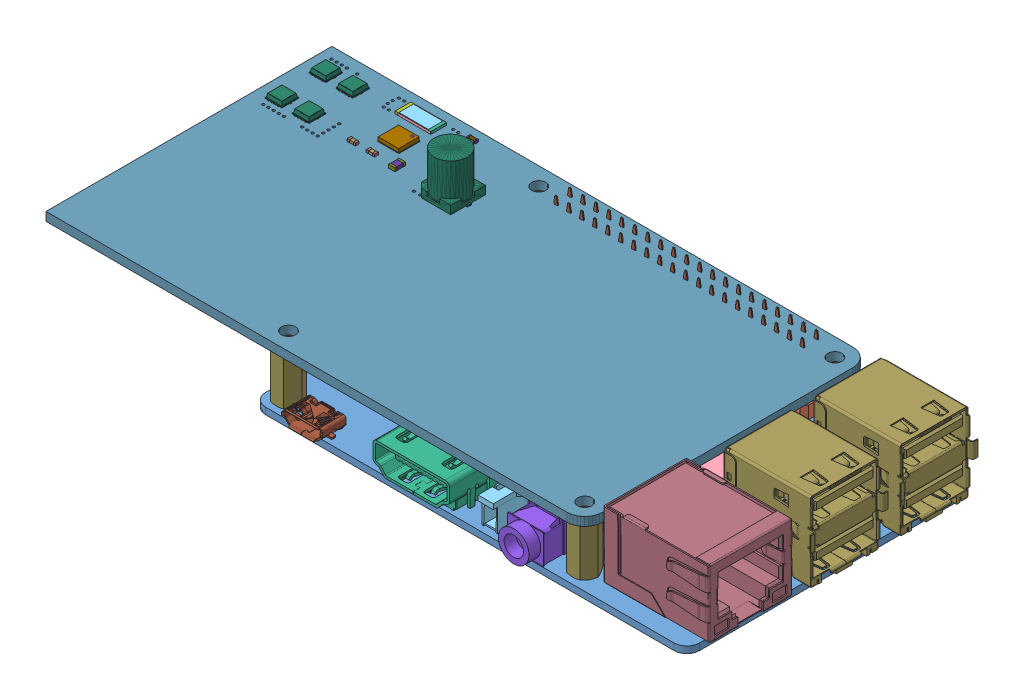
SolidWorks assembly RaspberryPi2 STEP214, configuration Default. Lengths in mm.
Overall size (130.68 29.46 66.29).
230 component instances, 66 part files, 14 mates.
Components (placement in the parent):
- Mainboard2-1: Mainboard2 [Default] at origin size (85 1.3 56)
- GPIO-1: GPIO [Default] at (-11.37 0 -24.5) x (0 0 1) z (-1 0 0) size (5 11.5 50.8)
- Processor-1: Processor [Default] at (-15.5 0 -3) x (0 0 1) z (-1 0 0) size (14 1 14)
- GPU-1: GPU [Default] at (15.25 0 -5.75) x (0 0 1) z (-1 0 0) size (9.1 1 9.1)
- CameraAssembly-1: CameraAssembly [Default] at (10.0885 -2.9159 16.55) x (-1 0 0) z (0 0 -1) size (6.09 6.17 23.84)
- CameraAssembly-2: CameraAssembly [Default] at (-46.3885 -2.9159 0) size (6.09 6.17 23.84)
- HDMI-1: HDMI [Default] at (-10.2 0.27 29.3) size (15 8.38 12.15)
- RAM-1: RAM [Default] at (0.5 -2.3 -6) x (0 0 1) z (-1 0 0) size (12 1 12)
- Audio-1: Audio [Default] at (10.9 0.15 21.75) size (7 6 14.8)
- MicroSDSocket-1: MicroSDSocket [Default] at (-34.5 -1.3 -0.7) x (0 0 -1) z (-1 0 0) size (13 1.3 14)
- MicroSD-1: MicroSD [Default] at (-37 -2.3 0.1) x (0 0 1) z (-1 0 0) size (11.29 1 15)
- micro USB2-1: micro USB2 [Default] at (-17.2704 -5.0969 44.9026) size (22.78 22.78 22.78)
- usb double-1: usb double [Default] at (30.38 -0.09 -18.85) x (0 0 -1) z (1 0 0) size (15.6 18.75 17.92)
- usb double-2: usb double [Default] at (30.38 -0.09 -1.25) x (0 0 -1) z (1 0 0) size (15.6 18.75 17.92)
- RJ45-LED-1: RJ45-LED [Default] at (34.11 7.4 17.348) x (1 0 0) z (0 -1 0) size (24.17 19.48 18.18)
- Motor_Control_Board-1: Motor_Control_Board [Default] at (-170 11.6914 170) x (1 0 0) z (0 1 0) size (105.51 56.01 9.74)
  - Board-1: Board [Default] at (0 0 -1.6914) size (105.51 56.01 1.69)
  - C1-1: C1 [Default] at origin size (7.39 6.81 8.05)
    - PCAP_6_3x7_7-ELECT-M-1: PCAP_6_3x7_7-ELECT-M [Default] at (123.8505 184.4041 0) x (1 0 0) z (0 0 1) size (7.39 6.81 8.05)
  - C2-1: C2 [Default] at origin size (1.27 2.06 0.66)
    - 642826464-1: 642826464 [Default] at (113.8174 184.7342 0) size (1.27 0.41 0.66)
      - Extruded-1: Extruded [Default] at origin size (1.27 0.41 0.66)
    - 642826464-2: 642826464 [Default] at (113.8174 183.0832 0) size (1.27 0.41 0.66)
      - Extruded-1: Extruded [Default] at origin size (1.27 0.41 0.66)
    - 642826720-1: 642826720 [Default] at (113.8174 183.9087 0) size (1.22 2.01 0.64)
      - Extruded_2-1: Extruded_2 [Default] at origin size (1.22 2.01 0.64)
    - 642825824-1: 642825824 [Default] at (114.0079 184.2834 0.5588) size (0.38 0.19 0.03)
      - Extruded_3-1: Extruded_3 [Default] at origin size (0.38 0.19 0.03)
    - 642829792-1: 642829792 [Default] at (114.0079 184.0293 0.5588) size (0.38 0.19 0.13)
      - Extruded_4-1: Extruded_4 [Default] at origin size (0.38 0.19 0.13)
    - 642829664-1: 642829664 [Default] at (114.0079 183.2673 0.5588) size (0.38 0.25 0.13)
      - Extruded_5-1: Extruded_5 [Default] at origin size (0.38 0.25 0.13)
    - 642829536-1: 642829536 [Default] at (114.0079 183.7753 0.5588) size (0.38 0.25 0.13)
      - Extruded_6-1: Extruded_6 [Default] at origin size (0.38 0.25 0.13)
    - 642829408-1: 642829408 [Default] at (113.5634 183.8896 0.5588) size (0.38 0.19 0.03)
      - Extruded_7-1: Extruded_7 [Default] at origin size (0.38 0.19 0.03)
    - 642829280-1: 642829280 [Default] at (113.5634 183.6357 0.5588) size (0.38 0.19 0.03)
      - Extruded_8-1: Extruded_8 [Default] at origin size (0.38 0.19 0.03)
    - 642829152-1: 642829152 [Default] at (113.5634 183.3817 0.5588) size (0.38 0.19 0.03)
      - Extruded_9-1: Extruded_9 [Default] at origin size (0.38 0.19 0.03)
    - 642829024-1: 642829024 [Default] at (113.5634 183.1277 0.5588) size (0.38 0.25 0.13)
      - Extruded_10-1: Extruded_10 [Default] at origin size (0.38 0.25 0.13)
    - 642828896-1: 642828896 [Default] at (114.0079 183.5213 0.5588) size (0.38 0.19 0.03)
      - Extruded_11-1: Extruded_11 [Default] at origin size (0.38 0.19 0.03)
    - 642828768-1: 642828768 [Default] at (113.5634 184.1436 0.5588) size (0.38 0.19 0.03)
      - Extruded_12-1: Extruded_12 [Default] at origin size (0.38 0.19 0.03)
    - 642828512-1: 642828512 [Default] at (113.5634 184.3976 0.5588) size (0.38 0.19 0.03)
      - Extruded_13-1: Extruded_13 [Default] at origin size (0.38 0.19 0.03)
  - C3-1: C3 [Default] at origin size (1.6 0.76 0.48)
    - 642828384-1: 642828384 [Default] at (109.6518 183.5634 0.254) size (0.13 0.25 0.03)
      - Extruded_14-1: Extruded_14 [Default] at origin size (0.13 0.25 0.03)
    - 642828128-1: 642828128 [Default] at (109.1565 183.7412 0) size (1.55 0.71 0.46)
      - Extruded_15-1: Extruded_15 [Default] at origin size (1.55 0.71 0.46)
    - 642828000-1: 642828000 [Default] at (109.7534 183.7412 0) size (0.41 0.76 0.48)
      - Extruded_16-1: Extruded_16 [Default] at origin size (0.41 0.76 0.48)
    - 642828000-2: 642828000 [Default] at (108.5596 183.7412 0) size (0.41 0.76 0.48)
      - Extruded_16-1: Extruded_16 [Default] at origin size (0.41 0.76 0.48)
    - 642827872-1: 642827872 [Default] at (109.2708 183.5634 0.254) size (0.13 0.25 0.03)
      - Extruded_17-1: Extruded_17 [Default] at origin size (0.13 0.25 0.03)
    - 642827616-1: 642827616 [Default] at (109.2708 183.9444 0.254) size (0.13 0.25 0.03)
      - Extruded_18-1: Extruded_18 [Default] at origin size (0.13 0.25 0.03)
    - 642827488-1: 642827488 [Default] at (109.0803 183.9444 0.254) size (0.13 0.25 0.03)
      - Extruded_19-1: Extruded_19 [Default] at origin size (0.13 0.25 0.03)
    - 642827360-1: 642827360 [Default] at (108.6993 183.9444 0.254) size (0.19 0.25 0.13)
      - Extruded_20-1: Extruded_20 [Default] at origin size (0.19 0.25 0.13)
    - 642827232-1: 642827232 [Default] at (108.8898 183.9444 0.254) size (0.13 0.25 0.03)
      - Extruded_21-1: Extruded_21 [Default] at origin size (0.13 0.25 0.03)
    - 642826976-1: 642826976 [Default] at (109.4613 183.9444 0.254) size (0.13 0.25 0.03)
      - Extruded_22-1: Extruded_22 [Default] at origin size (0.13 0.25 0.03)
    - 642827104-1: 642827104 [Default] at (109.6518 183.9444 0.254) size (0.13 0.25 0.03)
      - Extruded_23-1: Extruded_23 [Default] at origin size (0.13 0.25 0.03)
    - 642829920-1: 642829920 [Default] at (109.0803 183.5634 0.254) size (0.13 0.25 0.03)
      - Extruded_24-1: Extruded_24 [Default] at origin size (0.13 0.25 0.03)
    - 642830176-1: 642830176 [Default] at (108.8898 183.5634 0.254) size (0.13 0.25 0.03)
      - Extruded_25-1: Extruded_25 [Default] at origin size (0.13 0.25 0.03)
    - 642830304-1: 642830304 [Default] at (108.6993 183.5634 0.254) size (0.13 0.25 0.03)
      - Extruded_26-1: Extruded_26 [Default] at origin size (0.13 0.25 0.03)
  - C4-1: C4 [Default] at origin size (1.6 0.76 0.48)
    - 642830432-1: 642830432 [Default] at (116.2812 194.3608 0.254) size (0.13 0.25 0.03)
      - Extruded_27-1: Extruded_27 [Default] at origin size (0.13 0.25 0.03)
    - 642828128-1: 642828128 [Default] at (116.7765 194.183 0) size (1.55 0.71 0.46)
      - Extruded_15-1: Extruded_15 [Default] at origin size (1.55 0.71 0.46)
    - 642828000-1: 642828000 [Default] at (116.1796 194.183 0) size (0.41 0.76 0.48)
      - Extruded_16-1: Extruded_16 [Default] at origin size (0.41 0.76 0.48)
    - 642828000-2: 642828000 [Default] at (117.3734 194.183 0) size (0.41 0.76 0.48)
      - Extruded_16-1: Extruded_16 [Default] at origin size (0.41 0.76 0.48)
    - 642830688-1: 642830688 [Default] at (116.6622 194.3608 0.254) size (0.13 0.25 0.03)
      - Extruded_28-1: Extruded_28 [Default] at origin size (0.13 0.25 0.03)
    - 642830816-1: 642830816 [Default] at (116.6622 193.9798 0.254) size (0.13 0.25 0.03)
      - Extruded_29-1: Extruded_29 [Default] at origin size (0.13 0.25 0.03)
    - 577140176-1: 577140176 [Default] at (116.8527 193.9798 0.254) size (0.13 0.25 0.03)
      - Extruded_30-1: Extruded_30 [Default] at origin size (0.13 0.25 0.03)
    - 642827360-1: 642827360 [Default] at (117.2337 193.9798 0.254) size (0.19 0.25 0.13)
      - Extruded_20-1: Extruded_20 [Default] at origin size (0.19 0.25 0.13)
    - 477870864-1: 477870864 [Default] at (117.0432 193.9798 0.254) size (0.13 0.25 0.03)
      - Extruded_31-1: Extruded_31 [Default] at origin size (0.13 0.25 0.03)
    - 642828640-1: 642828640 [Default] at (116.4717 193.9798 0.254) size (0.13 0.25 0.03)
      - Extruded_32-1: Extruded_32 [Default] at origin size (0.13 0.25 0.03)
    - 577140432-1: 577140432 [Default] at (116.2812 193.9798 0.254) size (0.13 0.25 0.03)
      - Extruded_33-1: Extruded_33 [Default] at origin size (0.13 0.25 0.03)
    - 642829920-1: 642829920 [Default] at (116.8527 194.3608 0.254) size (0.13 0.25 0.03)
      - Extruded_24-1: Extruded_24 [Default] at origin size (0.13 0.25 0.03)
    - 577140560-1: 577140560 [Default] at (117.0432 194.3608 0.254) size (0.13 0.25 0.03)
      - Extruded_34-1: Extruded_34 [Default] at origin size (0.13 0.25 0.03)
    - 577140688-1: 577140688 [Default] at (117.2337 194.3608 0.254) size (0.13 0.25 0.03)
      - Extruded_35-1: Extruded_35 [Default] at origin size (0.13 0.25 0.03)
  - C5-1: C5 [Default] at origin size (1.6 0.76 0.48)
    - 642828384-1: 642828384 [Default] at (105.9166 183.5634 0.254) size (0.13 0.25 0.03)
      - Extruded_14-1: Extruded_14 [Default] at origin size (0.13 0.25 0.03)
    - 642828128-1: 642828128 [Default] at (105.4213 183.7412 0) size (1.55 0.71 0.46)
      - Extruded_15-1: Extruded_15 [Default] at origin size (1.55 0.71 0.46)
    - 642828000-1: 642828000 [Default] at (106.0182 183.7412 0) size (0.41 0.76 0.48)
      - Extruded_16-1: Extruded_16 [Default] at origin size (0.41 0.76 0.48)
    - 642828000-2: 642828000 [Default] at (104.8244 183.7412 0) size (0.41 0.76 0.48)
      - Extruded_16-1: Extruded_16 [Default] at origin size (0.41 0.76 0.48)
    - 642827872-1: 642827872 [Default] at (105.5356 183.5634 0.254) size (0.13 0.25 0.03)
      - Extruded_17-1: Extruded_17 [Default] at origin size (0.13 0.25 0.03)
    - 642827616-1: 642827616 [Default] at (105.5356 183.9444 0.254) size (0.13 0.25 0.03)
      - Extruded_18-1: Extruded_18 [Default] at origin size (0.13 0.25 0.03)
    - 642827488-1: 642827488 [Default] at (105.3451 183.9444 0.254) size (0.13 0.25 0.03)
      - Extruded_19-1: Extruded_19 [Default] at origin size (0.13 0.25 0.03)
    - 642827360-1: 642827360 [Default] at (104.9641 183.9444 0.254) size (0.19 0.25 0.13)
      - Extruded_20-1: Extruded_20 [Default] at origin size (0.19 0.25 0.13)
    - 642827232-1: 642827232 [Default] at (105.1546 183.9444 0.254) size (0.13 0.25 0.03)
      - Extruded_21-1: Extruded_21 [Default] at origin size (0.13 0.25 0.03)
    - 642826976-1: 642826976 [Default] at (105.7261 183.9444 0.254) size (0.13 0.25 0.03)
      - Extruded_22-1: Extruded_22 [Default] at origin size (0.13 0.25 0.03)
    - 642827104-1: 642827104 [Default] at (105.9166 183.9444 0.254) size (0.13 0.25 0.03)
      - Extruded_23-1: Extruded_23 [Default] at origin size (0.13 0.25 0.03)
    - 642829920-1: 642829920 [Default] at (105.3451 183.5634 0.254) size (0.13 0.25 0.03)
      - Extruded_24-1: Extruded_24 [Default] at origin size (0.13 0.25 0.03)
    - 642830176-1: 642830176 [Default] at (105.1546 183.5634 0.254) size (0.13 0.25 0.03)
      - Extruded_25-1: Extruded_25 [Default] at origin size (0.13 0.25 0.03)
    - 642830304-1: 642830304 [Default] at (104.9641 183.5634 0.254) size (0.13 0.25 0.03)
      - Extruded_26-1: Extruded_26 [Default] at origin size (0.13 0.25 0.03)
  - Q1-1: Q1 [Default] at origin size (3.99 3.99 1.61)
    - PowerPAK_1212-8_Single_Pad-1: PowerPAK_1212-8_Single_Pad [Default] at (96.1999 192.9 0) x (1 0 0) z (0 -1 0) size (3.99 1.6 3.99)
    - PowerPAK_1212-8_Single_Pad_2-1: PowerPAK_1212-8_Single_Pad_2 [Default] at (96.1999 192.9 0) x (1 0 0) z (0 -1 0) size (3.55 0.28 3.55)
  - Q2-1: Q2 [Default] at origin size (3.99 3.99 1.61)
    - PowerPAK_1212-8_Single_Pad-1: PowerPAK_1212-8_Single_Pad [Default] at (96.2001 184.3 0) x (-1 0 0) z (0 1 0) size (3.99 1.6 3.99)
    - PowerPAK_1212-8_Single_Pad_2-1: PowerPAK_1212-8_Single_Pad_2 [Default] at (96.2001 184.3 0) x (-1 0 0) z (0 1 0) size (3.55 0.28 3.55)
  - Q3-1: Q3 [Default] at origin size (3.99 3.99 1.61)
    - PowerPAK_1212-8_Single_Pad-1: PowerPAK_1212-8_Single_Pad [Default] at (90.9001 192.8999 0) x (-1 0 0) z (0 1 0) size (3.99 1.6 3.99)
    - PowerPAK_1212-8_Single_Pad_2-1: PowerPAK_1212-8_Single_Pad_2 [Default] at (90.9001 192.8999 0) x (-1 0 0) z (0 1 0) size (3.55 0.28 3.55)
  - Q4-1: Q4 [Default] at origin size (3.99 3.99 1.61)
    - PowerPAK_1212-8_Single_Pad-1: PowerPAK_1212-8_Single_Pad [Default] at (90.8999 184.3 0) x (1 0 0) z (0 -1 0) size (3.99 1.6 3.99)
    - PowerPAK_1212-8_Single_Pad_2-1: PowerPAK_1212-8_Single_Pad_2 [Default] at (90.8999 184.3 0) x (1 0 0) z (0 -1 0) size (3.55 0.28 3.55)
  - R1-1: R1 [Default] at origin size (1.6 0.76 0.48)
    - 642830304-1: 642830304 [Default] at (116.3828 192.5193 0.381) size (0.13 0.25 0.03)
      - Extruded_26-1: Extruded_26 [Default] at origin size (0.13 0.25 0.03)
    - 642830176-1: 642830176 [Default] at (116.5733 192.5193 0.381) size (0.13 0.25 0.03)
      - Extruded_25-1: Extruded_25 [Default] at origin size (0.13 0.25 0.03)
    - 642829920-1: 642829920 [Default] at (116.7638 192.5193 0.381) size (0.13 0.25 0.03)
      - Extruded_24-1: Extruded_24 [Default] at origin size (0.13 0.25 0.03)
    - 642827104-1: 642827104 [Default] at (117.2464 192.7987 0.381) size (0.13 0.25 0.03)
      - Extruded_23-1: Extruded_23 [Default] at origin size (0.13 0.25 0.03)
    - 642826976-1: 642826976 [Default] at (117.0559 192.7987 0.381) size (0.13 0.25 0.03)
      - Extruded_22-1: Extruded_22 [Default] at origin size (0.13 0.25 0.03)
    - 642827232-1: 642827232 [Default] at (116.4844 192.7987 0.381) size (0.13 0.25 0.03)
      - Extruded_21-1: Extruded_21 [Default] at origin size (0.13 0.25 0.03)
    - 577140816-1: 577140816 [Default] at (116.0907 192.659 0) size (0.23 0.76 0.48)
      - Extruded_36-1: Extruded_36 [Default] at origin size (0.23 0.76 0.48)
    - 577140816-2: 577140816 [Default] at (117.4623 192.659 0) size (0.23 0.76 0.48)
      - Extruded_36-1: Extruded_36 [Default] at origin size (0.23 0.76 0.48)
    - 577140944-1: 577140944 [Default] at (116.7765 192.659 0.4572) size (1.14 0.66 0.03)
      - Extruded_37-1: Extruded_37 [Default] at origin size (1.14 0.66 0.03)
    - 577141072-1: 577141072 [Default] at (116.7765 192.659 0) size (1.55 0.71 0.46)
      - Extruded_38-1: Extruded_38 [Default] at origin size (1.55 0.71 0.46)
    - 642827360-1: 642827360 [Default] at (116.2939 192.7987 0.381) size (0.19 0.25 0.13)
      - Extruded_20-1: Extruded_20 [Default] at origin size (0.19 0.25 0.13)
    - 642827488-1: 642827488 [Default] at (116.6749 192.7987 0.381) size (0.13 0.25 0.03)
      - Extruded_19-1: Extruded_19 [Default] at origin size (0.13 0.25 0.03)
    - 642827616-1: 642827616 [Default] at (116.8654 192.7987 0.381) size (0.13 0.25 0.03)
      - Extruded_18-1: Extruded_18 [Default] at origin size (0.13 0.25 0.03)
    - 642827872-1: 642827872 [Default] at (116.9543 192.5193 0.381) size (0.13 0.25 0.03)
      - Extruded_17-1: Extruded_17 [Default] at origin size (0.13 0.25 0.03)
    - 577141456-1: 577141456 [Default] at (117.1448 192.5193 0.381) size (0.14 0.25 0.13)
      - Extruded_39-1: Extruded_39 [Default] at origin size (0.14 0.25 0.13)
  - R2-1: R2 [Default] at origin size (1.6 0.76 0.48)
    - 577140688-1: 577140688 [Default] at (117.1702 195.8467 0.381) size (0.13 0.25 0.03)
      - Extruded_35-1: Extruded_35 [Default] at origin size (0.13 0.25 0.03)
    - 577140560-1: 577140560 [Default] at (116.9797 195.8467 0.381) size (0.13 0.25 0.03)
      - Extruded_34-1: Extruded_34 [Default] at origin size (0.13 0.25 0.03)
    - 642829920-1: 642829920 [Default] at (116.7892 195.8467 0.381) size (0.13 0.25 0.03)
      - Extruded_24-1: Extruded_24 [Default] at origin size (0.13 0.25 0.03)
    - 577140432-1: 577140432 [Default] at (116.3066 195.5673 0.381) size (0.13 0.25 0.03)
      - Extruded_33-1: Extruded_33 [Default] at origin size (0.13 0.25 0.03)
    - 642828640-1: 642828640 [Default] at (116.4971 195.5673 0.381) size (0.13 0.25 0.03)
      - Extruded_32-1: Extruded_32 [Default] at origin size (0.13 0.25 0.03)
    - 477870864-1: 477870864 [Default] at (117.0686 195.5673 0.381) size (0.13 0.25 0.03)
      - Extruded_31-1: Extruded_31 [Default] at origin size (0.13 0.25 0.03)
    - 577140816-1: 577140816 [Default] at (117.4623 195.707 0) size (0.23 0.76 0.48)
      - Extruded_36-1: Extruded_36 [Default] at origin size (0.23 0.76 0.48)
    - 577140816-2: 577140816 [Default] at (116.0907 195.707 0) size (0.23 0.76 0.48)
      - Extruded_36-1: Extruded_36 [Default] at origin size (0.23 0.76 0.48)
    - 577140944-1: 577140944 [Default] at (116.7765 195.707 0.4572) size (1.14 0.66 0.03)
      - Extruded_37-1: Extruded_37 [Default] at origin size (1.14 0.66 0.03)
    - 577141072-1: 577141072 [Default] at (116.7765 195.707 0) size (1.55 0.71 0.46)
      - Extruded_38-1: Extruded_38 [Default] at origin size (1.55 0.71 0.46)
    - 642827360-1: 642827360 [Default] at (117.2591 195.5673 0.381) size (0.19 0.25 0.13)
      - Extruded_20-1: Extruded_20 [Default] at origin size (0.19 0.25 0.13)
    - 577140176-1: 577140176 [Default] at (116.8781 195.5673 0.381) size (0.13 0.25 0.03)
      - Extruded_30-1: Extruded_30 [Default] at origin size (0.13 0.25 0.03)
    - 642830816-1: 642830816 [Default] at (116.6876 195.5673 0.381) size (0.13 0.25 0.03)
      - Extruded_29-1: Extruded_29 [Default] at origin size (0.13 0.25 0.03)
    - 642830688-1: 642830688 [Default] at (116.5987 195.8467 0.381) size (0.13 0.25 0.03)
      - Extruded_28-1: Extruded_28 [Default] at origin size (0.13 0.25 0.03)
    - 577141200-1: 577141200 [Default] at (116.4082 195.8467 0.381) size (0.14 0.25 0.13)
      - Extruded_40-1: Extruded_40 [Default] at origin size (0.14 0.25 0.13)
  - R3-1: R3 [Default] at origin size (6.99 3.09 0.48)
    - 577141712-1: 577141712 [Default] at (108.135 194.2764 0) size (6.9 3.09 0.46)
      - Extruded_41-1: Extruded_41 [Default] at origin size (6.9 3.09 0.46)
    - 577141840-1: 577141840 [Default] at (108.135 194.2827 0.4572) size (5.78 2.84 0.03)
      - Extruded_42-1: Extruded_42 [Default] at origin size (5.78 2.84 0.03)
    - 577141968-1: 577141968 [Default] at (111.3228 194.2764 0) size (0.6 3.09 0.48)
      - Extruded_43-1: Extruded_43 [Default] at origin size (0.6 3.09 0.48)
    - 477873424-1: 477873424 [Default] at (104.941 194.2764 0) size (0.61 3.09 0.48)
      - Extruded_44-1: Extruded_44 [Default] at origin size (0.61 3.09 0.48)
  - U1-1: U1 [Default] at origin size (4.15 4.15 0.8)
    - 577142096-1: 577142096 [Default] at (110.9011 189.8396 0.8) size (0.52 0.52 0.01)
      - Extruded_45-1: Extruded_45 [Default] at origin size (0.52 0.52 0.01)
    - 577141584-1: 577141584 [Default] at (109.6772 188.3918 0.1) size (4.01 4.01 0.7)
      - Extruded_46-1: Extruded_46 [Default] at origin size (4.01 4.01 0.7)
    - 577142224-1: 577142224 [Default] at (109.685 188.425 0.01) size (4.15 4.15 0.09)
      - Extruded_47-1: Extruded_47 [Default] at origin size (4.15 4.15 0.09)
- c-2-535585-0-s-3d-1: c-2-535585-0-s-3d [Default] at (-10.1 3.269 -24.4854) x (1 0 0) z (0 -1 0) size (50.8 5.03 9.91)
- 93655A096-1: 93655A096 [93655A096] at (-39 3.05 24.5) x (0 -1 0) z (0 0 1) size (14.19 5.2 4.5)
- 93655A096-2: 93655A096 [93655A096] at (19 3.05 24.5) x (0 -1 0) z (0 0 1) size (14.19 5.2 4.5)
- 93655A096-3: 93655A096 [93655A096] at (-39 3.05 -24.5) x (0 -1 0) z (0 0 1) size (14.19 5.2 4.5)
- 93655A096-4: 93655A096 [93655A096] at (19 3.05 -24.5) x (0 -1 0) z (0 0 1) size (14.19 5.2 4.5)
Mates (geometry in assembly coordinates):
- Concentric1: concentric anti-aligned: circle of Mainboard2-1; circle of Motor_Control_Board-1/Board-1
- Concentric2: concentric anti-aligned: circle of Mainboard2-1; circle of Motor_Control_Board-1/Board-1
- Coincident2: coincident aligned: plane of GPIO-1 through (15.3 0 -23) normal (1 0 0); plane of c-2-535585-0-s-3d-1 through (15.3 2.5 -26.873) normal (1 0 0)
- Coincident3: coincident aligned: plane of GPIO-1 through (-15.85 0 -27) normal (0 0 -1); plane of c-2-535585-0-s-3d-1 through (-35.373 2.5 -27) normal (0 0 -1)
- Concentric3: concentric: circle of Mainboard2-1; cylinder of 93655A096-4 through (19 3.05 -24.5) axis (0 1 0) radius 0.9552
- Coincident7: coincident anti-aligned: plane of Mainboard2-1 through (40 0 25.5) normal (0 1 0); plane of 93655A096-4 through (21.5981 0 -24.5) normal (0 -1 0)
- Concentric4: concentric: circle of Mainboard2-1; cylinder of 93655A096-3 through (-39 3.05 -24.5) axis (0 1 0) radius 0.9552
- Coincident8: coincident anti-aligned: plane of Mainboard2-1 through (40 0 25.5) normal (0 1 0); plane of 93655A096-3 through (-36.4019 0 -24.5) normal (0 -1 0)
- Concentric5: concentric: circle of Mainboard2-1; cylinder of 93655A096-1 through (-39 3.05 24.5) axis (0 1 0) radius 0.9552
- Coincident9: coincident anti-aligned: plane of Mainboard2-1 through (40 0 25.5) normal (0 1 0); plane of 93655A096-1 through (-36.4019 0 24.5) normal (0 -1 0)
- Concentric6: concentric anti-aligned: circle of Mainboard2-1; cylinder of 93655A096-2 through (19 3.05 24.5) axis (0 1 0) radius 0.9552
- Coincident10: coincident anti-aligned: plane of Mainboard2-1 through (40 0 25.5) normal (0 1 0); plane of 93655A096-2 through (21.5981 0 24.5) normal (0 -1 0)
- Coincident11: coincident anti-aligned: plane of Motor_Control_Board-1/Board-1 through (19 10 28) normal (0 -1 0); plane of 93655A096-2 through (21.5981 10 24.5) normal (0 1 0)
- Coincident12: coincident anti-aligned: plane of Motor_Control_Board-1/Board-1 through (19 10 28) normal (0 -1 0); plane of c-2-535585-0-s-3d-1 through (-10.1 10 -24.4854) normal (0 1 0)
